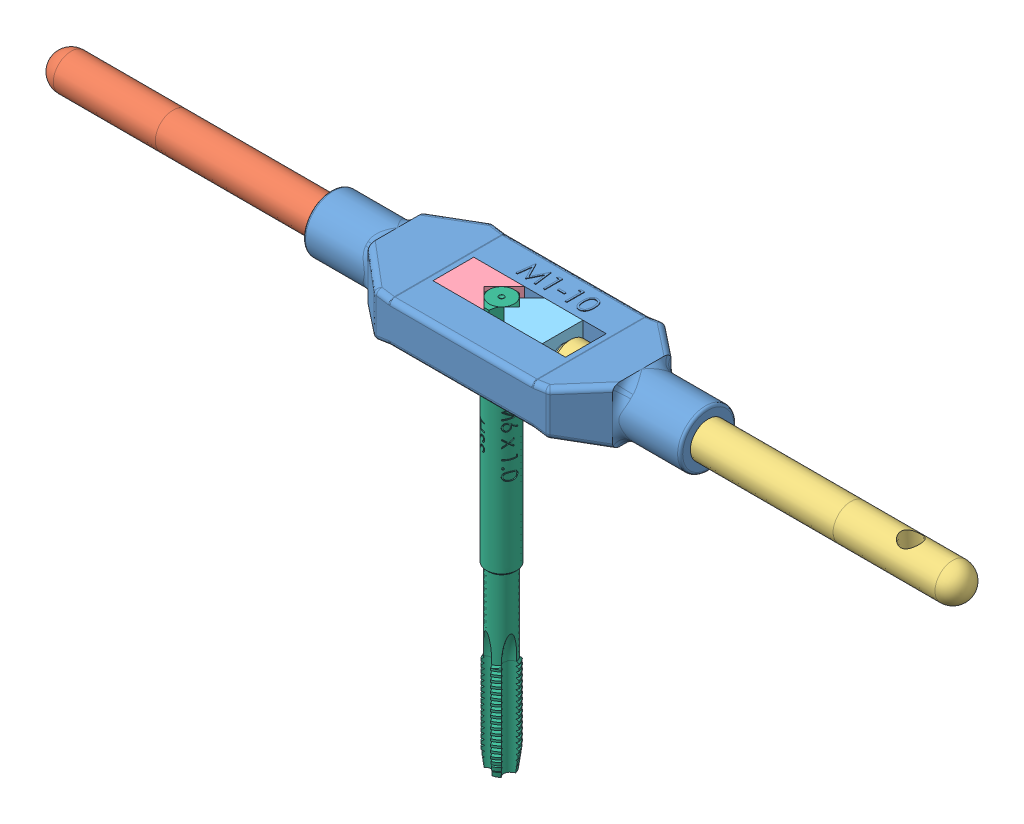
SolidWorks assembly TapWrench, configuration Default. Lengths in mm.
Overall size (180 81.58 23).
6 component instances, 6 part files, 13 mates.
Components (placement in the parent):
- Body-1: Body [Default] at origin size (74 11.16 23)
- FixedHandle-1: FixedHandle [Default] at (-14 4 -11.5) x (0 -0.837193 -0.546908) z (0 0.546908 -0.837193) size (7.03 63.5 7.03)
- AdjustableHandle-1: AdjustableHandle [Default] at (23 4 -11.5) x (0 0.074327 -0.997234) z (0 -0.997234 -0.074327) size (7.03 79.5 7.03)
- FixedHolder-1: FixedHolder [Default] at (1 0 -7.5) size (15 8 8)
- AdjustableHolder-1: AdjustableHolder [Default] at (8.9296 0 -7.5) size (24 8 8)
- M6SecondTap-1: M6SecondTap [Default] at (10.4648 -72 -11.5) x (0.707107 0 -0.707107) z (0.707107 0 0.707107) size (6.68 80 6.69)
Mates (geometry in assembly coordinates):
- Concentric1: concentric aligned: cylinder of FixedHandle-1 through (-54 4 -11.5) axis (1 0 0) radius 3.5; cylinder of Body-1 through (-23 4 -11.5) axis (1 0 0) radius 5.5
- Distance1: distance = 9 mm anti-aligned: plane of FixedHandle-1 through (-14 4 -11.5) normal (1 0 0); plane of Body-1 through (-23 4 -11.5) normal (-1 0 0)
- Concentric2: concentric aligned: cylinder of AdjustableHandle-1 through (48 4 -11.5) axis (-1 0 0) radius 3.5; cylinder of Body-1 through (51 4 -11.5) axis (-1 0 0) radius 5.5
- Distance2: distance = 28 mm anti-aligned: plane of AdjustableHandle-1 through (23 4 -11.5) normal (-1 0 0); plane of Body-1 through (51 4 -11.5) normal (1 0 0)
- Concentric3: concentric aligned: cylinder of Body-1 through (-4 4 -11.5) axis (1 0 0) radius 2; cylinder of FixedHolder-1 through (-4 4 -11.5) axis (1 0 0) radius 2
- Coincident2: coincident aligned: plane of Body-1 through (0 8 -23) normal (0 1 0); plane of FixedHolder-1 through (1 8 -15.5) normal (0 1 0)
- Coincident3: coincident anti-aligned: plane of Body-1 through (1 0 -15.5) normal (1 0 0); plane of FixedHolder-1 through (1 8 -7.5) normal (-1 0 0)
- Coincident4: coincident aligned: plane of Body-1 through (0 8 -23) normal (0 1 0); plane of AdjustableHolder-1 through (23.9671 8 -15.5) normal (0 1 0)
- Concentric4: concentric aligned: cylinder of Body-1 through (51 4 -11.5) axis (-1 0 0) radius 5.5; cylinder of AdjustableHolder-1 through (27.9671 4 -11.5) axis (-1 0 0) radius 1.9999
- Coincident5: coincident anti-aligned: plane of FixedHolder-1 through (7 8 -11.5) normal (0.707107 0 -0.707107); plane of M6SecondTap-1 through (8.7678 0 -9.7322) normal (-0.707107 0 0.707107)
- Coincident6: coincident anti-aligned: plane of FixedHolder-1 through (11 8 -15.5) normal (0.707107 0 0.707107); plane of M6SecondTap-1 through (1.2777 0 -5.7777) normal (-0.707107 0 -0.707107)
- Coincident7: coincident aligned: plane of FixedHolder-1 through (1 8 -15.5) normal (0 1 0); plane of M6SecondTap-1 through (10.4648 8 -11.5) normal (0 1 0)
- Coincident8: coincident anti-aligned: plane of AdjustableHolder-1 through (13.9296 8 -11.5) normal (-0.707107 0 0.707107); plane of M6SecondTap-1 through (12.2326 0 -13.197) normal (0.707107 0 -0.707107)
